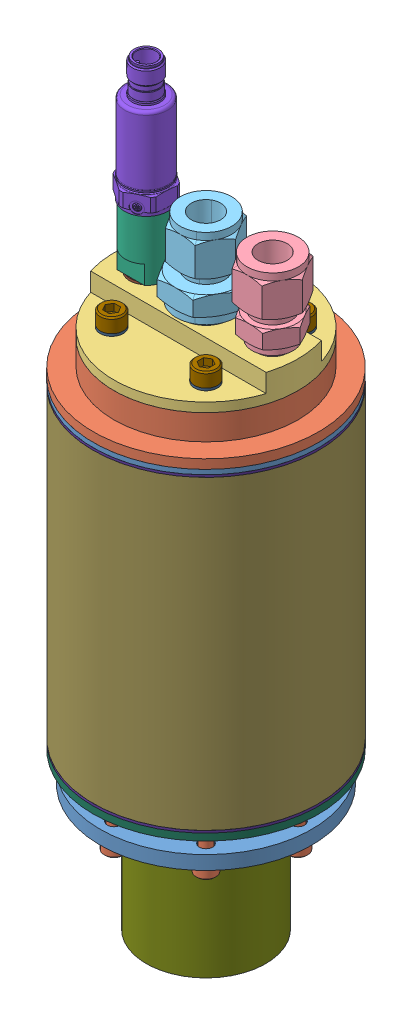
SolidWorks assembly Demo A2 98mm V02, configuration Standard. Lengths in mm.
Overall size (138.59 315.92 138.59).
37 component instances, 20 part files, 27 mates.
Components (placement in the parent):
- Injector 98mm V02-1: Injector 98mm V02 [Standard] at (0 -14 0) size (138.59 129.3 138.59)
  - Faceplate 98mm-1: Faceplate 98mm [Standard] x (-0.707107 0 -0.707107) z (0.707107 0 -0.707107) size (98 14 98)
  - Manifold 98mm-1: Manifold 98mm [Standard] at (0 14 0) size (98 15 98)
  - Core 98mm-1: Core 98mm [Standard] at (0 -3 0) size (80 44 80)
  - SS-810-1-4RS-SwagelokCompany-3D-10-18-2022.stp-1: SS-810-1-4RS-SwagelokCompany-3D-10-18-2022.stp [Standard] at (29 75.766 0) x (0 -1 0) z (-0.5 0 0.866025) size (44.7 22.35 25.81)
  - SS-810-1-8RS-SwagelokCompany-3D-10-18-2022.stp-1: SS-810-1-8RS-SwagelokCompany-3D-10-18-2022.stp [Standard] at (0 76.528 0) x (0 -1 0) z (0.5 0 0.866025) size (47.5 26.99 31.16)
  - Pressure sensor tube-1: Pressure sensor tube [Standard] at (-26 -2 0) x (0 0 -1) z (1 0 0) size (18 70 18)
  - Diverter 98mm-1: Diverter 98mm [Standard] at (0 -7.2 0) x (0.998923 0 0.046395) z (-0.046395 0 0.998923) size (19 24.43 19)
  - CAD_STP_500_0186-1: CAD_STP_500_0186 [Standard] at (-26 48.3 0) x (0 1 0) z (-0.050182 0 0.99874) size (73.8 19.02 21)
    - CAD_STP_500_0186.stp-1: CAD_STP_500_0186.stp [Standard] at origin size (73.8 19.02 21)
      - _PL54XX_P1.stp-1: _PL54XX_P1.stp [Standard] at origin size (73.8 19.02 21)
  - CB6-25.stp-1: CB6-25.stp [Standard] at (-20.5061 34 20.5061) x (0 -1 0) z (0 0 1) size (31 10 10)
  - CB6-25.stp-2: CB6-25.stp [Standard] at (-20.5061 34 -20.5061) x (0 -1 0) z (-1 0 0) size (31 10 10)
  - CB6-25.stp-3: CB6-25.stp [Standard] at (20.5061 34 -20.5061) x (0 -1 0) z (0 0 -1) size (31 10 10)
  - CB6-25.stp-4: CB6-25.stp [Standard] at (20.5061 34 20.5061) x (0 -1 0) z (1 0 0) size (31 10 10)
  - M6 bolt seal-1: M6 bolt seal [Standard] at (-20.5061 34 20.5061) x (0.989025 0 -0.147746) z (0 -1 0) size (10 10 1)
  - M6 bolt seal-2: M6 bolt seal [Standard] at (-20.5061 34 -20.5061) x (0.147746 0 0.989025) z (0 -1 0) size (10 10 1)
  - M6 bolt seal-3: M6 bolt seal [Standard] at (20.5061 34 -20.5061) x (-0.989025 0 0.147746) z (0 -1 0) size (10 10 1)
  - M6 bolt seal-4: M6 bolt seal [Standard] at (20.5061 34 20.5061) x (-0.147746 0 -0.989025) z (0 -1 0) size (10 10 1)
  - Seal pressure sensor-1: Seal pressure sensor [Standard] at (-26 41 0) size (14.4 1 14.4)
- Chamber 98mm-1: Chamber 98mm [Standard] at (0 -69.5 0) x (-0.996776 0 0.080231) z (-0.080231 0 -0.996776) size (98 133 98)
- Thermal Insulation-1: Thermal Insulation [Standard] at (0 -12 0) x (0 0 1) z (0 -1 0) size (91.69 91.69 112)
- Thermal Insulation faceplate-1: Thermal Insulation faceplate [Standard] at (0 -14 0) x (-1 0 0) z (0 -1 0) size (91.7 91.7 2)
- Nozzle converging 98mm -1: Nozzle converging 98mm  [Standard] at (0 -120 0) x (0 -1 0) z (0 0 1) size (22 98.3 99.09)
- Nozzle diverging 98mm -1: Nozzle diverging 98mm  [Standard] at (0 -142.2 0) x (0 -1 0) z (-0.490695 0 0.871332) size (71.92 64 64)
- Seal chamber-1: Seal chamber [Standard] at (0 -2 0) x (0 -1 0) z (0 0 1) size (1 98 98)
- Seal chamber-2: Seal chamber [Standard] at (0 -136 0) x (0 -1 0) z (0 0 1) size (1 98 98)
- Seal nozzle-1: Seal nozzle [Standard] at (0 -142.2 0) x (0.805443 0 -0.592674) z (0 1 0) size (56 56 1)
- Nozzle Insert holder-1: Nozzle Insert holder [Standard] at (0 -147.2 0) x (-0.707107 0 -0.707107) z (-0.707107 0 0.707107) size (92 6 92)
- CB5-20.stp-1: CB5-20.stp [Standard] at (-40 -153.2 0) x (0 1 0) z (0 0 1) size (25 8.5 8.5)
- CB5-20.stp-2: CB5-20.stp [Standard] at (-28.2843 -153.2 28.2843) x (0 1 0) z (0.707107 0 0.707107) size (25 8.5 8.5)
- CB5-20.stp-3: CB5-20.stp [Standard] at (0 -153.2 40) x (0 1 0) z (1 0 0) size (25 8.5 8.5)
- CB5-20.stp-4: CB5-20.stp [Standard] at (28.2843 -153.2 28.2843) x (0 1 0) z (0.707107 0 -0.707107) size (25 8.5 8.5)
- CB5-20.stp-5: CB5-20.stp [Standard] at (40 -153.2 0) x (0 1 0) z (0 0 -1) size (25 8.5 8.5)
- CB5-20.stp-6: CB5-20.stp [Standard] at (28.2843 -153.2 -28.2843) x (0 1 0) z (-0.707107 0 -0.707107) size (25 8.5 8.5)
- CB5-20.stp-7: CB5-20.stp [Standard] at (0 -153.2 -40) x (0 1 0) z (-1 0 0) size (25 8.5 8.5)
- CB5-20.stp-8: CB5-20.stp [Standard] at (-28.2843 -153.2 -28.2843) x (0 1 0) z (-0.707107 0 0.707107) size (25 8.5 8.5)
Mates (geometry in assembly coordinates):
- Coincident1: coincident aligned: plane of Injector 98mm V02-1/Faceplate 98mm-1 through (34.6482 0 34.6482) normal (0 1 0)
- Concentric1: concentric: cylinder of Injector 98mm V02-1/SS-810-1-8RS-SwagelokCompany-3D-10-18-2022.stp-1 through (0 51.098 0) axis (0 -1 0) radius 6.35
- Concentric2: concentric anti-aligned: cylinder of Injector 98mm V02-1/Manifold 98mm-1 through (0 0 0) axis (0 -1 0) radius 40; cylinder of Thermal Insulation-1 through (0 -124 0) axis (0 1 0) radius 45.847
- Concentric3: concentric aligned: cylinder of Injector 98mm V02-1/Faceplate 98mm-1 through (0 -14 0) axis (0 -1 0) radius 46; cylinder of Chamber 98mm-1 through (0 -69.5 0) axis (0 -1 0) radius 49
- Distance1: distance = 1 mm anti-aligned: plane of Chamber 98mm-1 through (45.7022 -3 -3.6786) normal (0 1 0); plane of Injector 98mm V02-1/Faceplate 98mm-1 through (32.5269 -2 32.5269) normal (0 -1 0)
- Concentric4: concentric anti-aligned: cylinder of Injector 98mm V02-1/Core 98mm-1 through (0 -17 0) axis (0 -1 0) radius 7.5; cylinder of Thermal Insulation faceplate-1 through (0 -16 0) axis (0 1 0) radius 45.85
- Coincident5: coincident anti-aligned: plane of Injector 98mm V02-1/Faceplate 98mm-1 through (7.1418 -14 7.1418) normal (0 -1 0); plane of Thermal Insulation faceplate-1 through (0 -14 0) normal (0 1 0)
- Concentric5: concentric anti-aligned: cylinder of Chamber 98mm-1 through (0 -69.5 0) axis (0 -1 0) radius 45.85; cylinder of Nozzle converging 98mm -1 through (0 -120 0) axis (0 1 0) radius 26
- Concentric6: concentric aligned: cylinder of Nozzle converging 98mm -1 through (0 -120 0) axis (0 1 0) radius 26; cylinder of Nozzle diverging 98mm -1 through (0 -142.2 0) axis (0 1 0) radius 26
- Distance2: distance = 1 mm anti-aligned: plane of Nozzle diverging 98mm -1 through (22.6546 -142.2 12.7581) normal (0 1 0); plane of Nozzle converging 98mm -1 through (26 -141.2 0) normal (0 -1 0)
- Concentric7: concentric anti-aligned: cylinder of Injector 98mm V02-1/Manifold 98mm-1 through (0 0 0) axis (0 -1 0) radius 40; cylinder of Seal chamber-1 through (0 -3 0) axis (0 1 0) radius 47.5
- Coincident7: coincident anti-aligned: plane of Injector 98mm V02-1/Faceplate 98mm-1 through (32.5269 -2 32.5269) normal (0 -1 0); plane of Seal chamber-1 through (0 -2 0) normal (0 1 0)
- Concentric8: concentric anti-aligned: cylinder of Chamber 98mm-1 through (0 -69.5 0) axis (0 -1 0) radius 49; cylinder of Seal chamber-2 through (0 -137 0) axis (0 1 0) radius 47.5
- Coincident8: coincident anti-aligned: plane of Chamber 98mm-1 through (45.7022 -136 -3.6786) normal (0 -1 0); plane of Seal chamber-2 through (0 -136 0) normal (0 1 0)
- Coincident10: coincident anti-aligned: plane of Nozzle converging 98mm -1 through (46 -137 0) normal (0 1 0); plane of Seal chamber-2 through (0 -137 0) normal (0 -1 0)
- Concentric9: concentric anti-aligned: cylinder of Nozzle diverging 98mm -1 through (0 -142.2 0) axis (0 1 0) radius 26; cylinder of Seal nozzle-1 through (0 -141.2 0) axis (0 -1 0) radius 26
- Coincident11: coincident anti-aligned: plane of Nozzle converging 98mm -1 through (26 -141.2 0) normal (0 -1 0); plane of Seal nozzle-1 through (0 -141.2 0) normal (0 1 0)
- Concentric10: concentric aligned: cylinder of Nozzle diverging 98mm -1 through (0 -142.2 0) axis (0 1 0) radius 26; cylinder of Nozzle Insert holder-1 through (0 -147.2 0) axis (0 1 0) radius 32
- Coincident12: coincident anti-aligned: plane of Nozzle diverging 98mm -1 through (27.8826 -150.2 15.7022) normal (0 -1 0); plane of Nozzle Insert holder-1 through (18.3848 -150.2 18.3848) normal (0 1 0)
- Concentric11: concentric aligned: cylinder of Nozzle converging 98mm -1 through (-28.2843 -140 -28.2843) axis (0 -1 0) radius 2.1; cylinder of Nozzle Insert holder-1 through (-28.2843 -153.2 -28.2843) axis (0 -1 0) radius 2.9
- Concentric16: concentric anti-aligned: cylinder of Injector 98mm V02-1/Pressure sensor tube-1 through (-26 -16 0) axis (0 -1 0) radius 3; cylinder of Thermal Insulation faceplate-1 through (-26 -16.001 0) axis (0 1 0) radius 3
- Coincident13: coincident aligned: plane of Injector 98mm V02-1 through (0 -14 0) normal (0 0 1)
- Coincident14: coincident anti-aligned: plane of Thermal Insulation-1 through (0 -124 0) normal (0 -1 0); plane of Nozzle converging 98mm -1 through (42.865 -124 0) normal (0 1 0)
- Coincident15: coincident anti-aligned: plane of Thermal Insulation-1 through (45.847 -16 -6) normal (0 0 1); plane of Thermal Insulation faceplate-1 through (42.4379 -16.001 -6) normal (0 0 -1)
- Coincident16: coincident: unknown of Nozzle converging 98mm -1
- Concentric17: concentric anti-aligned: cylinder of Nozzle Insert holder-1 through (-40 -153.2 0) axis (0 -1 0) radius 2.9; cylinder of CB5-20.stp-1 through (-40 -133.2 0) axis (0 1 0) radius 2.5
- Coincident17: coincident anti-aligned: plane of Nozzle Insert holder-1 through (32.5269 -153.2 32.5269) normal (0 -1 0); plane of CB5-20.stp-1 through (-44.25 -153.2 0) normal (0 1 0)
